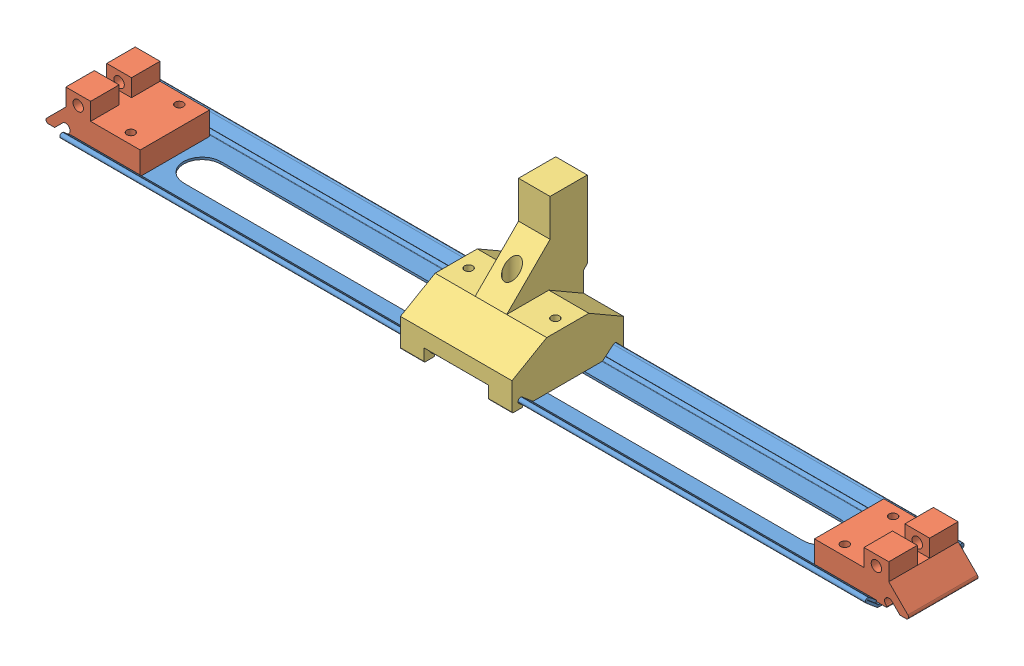
SolidWorks assembly bushing config, configuration Default. Lengths in mm.
Overall size (348 53.61 46.5).
4 component instances, 3 part files, 12 mates.
Components (placement in the parent):
- sheet metal gantry-1: sheet metal gantry [Default] at origin size (325 5.52 39.86)
- gantry holder-bushing-1: gantry holder-bushing [Default] at (-136 5.461 0) x (0 0 -1) z (-1 0 0) size (28 16.4 38)
- gantry holder-bushing-2: gantry holder-bushing [Default] at (136 5.588 0) x (0 0 1) z (1 0 0) size (28 16.4 38)
- hotend mount-bushing-1: hotend mount-bushing [Default] at (0 11.1125 0) x (0 0 1) z (1 0 0) size (46.5 52 45)
Mates (geometry in assembly coordinates):
- Coincident1: coordinate: point of sheet metal gantry-1; point of assembly
- Coincident2: coincident aligned: plane of ? through (-2.3369 1.8788 0) normal (0 0 1); plane of assembly through (0 0 0) normal (0 0 1)
- Tangent1: tangent anti-aligned: cylinder of sheet metal gantry-1 through (-162.5 4.8168 -18.6685) axis (-1 0 0) radius 0.812; plane of ? through (10.1631 5.6288 -8.4455) normal (0 -1 0)
- Coincident3: coincident anti-aligned: plane of gantry holder-bushing-1 through (-136 5.461 0) normal (0 0 -1); plane of assembly through (0 0 0) normal (0 0 1)
- Distance1: distance = 10.16 mm anti-aligned: plane of gantry holder-bushing-1 through (-166 10.16 -14) normal (0 1 0); plane of sheet metal gantry-1 through (162.5 0 15) normal (0 -1 0)
- Concentric1: concentric aligned: cylinder of sheet metal gantry-1 through (-144 0.889 9.75) axis (0 1 0) radius 2.15; cylinder of gantry holder-bushing-1 through (-144 10.16 9.75) axis (0 1 0) radius 1.65
- Concentric2: concentric aligned: cylinder of sheet metal gantry-1 through (144 0.889 -9.75) axis (0 1 0) radius 2.15; cylinder of gantry holder-bushing-2 through (144 10.287 -9.75) axis (0 1 0) radius 1.65
- Concentric3: concentric aligned: cylinder of sheet metal gantry-1 through (144 0.889 9.75) axis (0 1 0) radius 2.15; cylinder of gantry holder-bushing-2 through (144 10.287 9.75) axis (0 1 0) radius 1.65
- Coincident5: coincident anti-aligned: plane of sheet metal gantry-1 through (162.5 0.889 15) normal (0 1 0); plane of gantry holder-bushing-2 through (166 0.889 14) normal (0 -1 0)
- Coincident6: coincident aligned: plane of hotend mount-bushing-1 through (0 11.1125 0) normal (1 0 0); plane of assembly through (0 0 0) normal (1 0 0)
- Coincident7: coincident aligned: plane of hotend mount-bushing-1 through (0 11.1125 0) normal (0 0 1); plane of assembly through (0 0 0) normal (0 0 1)
- Coincident8: coincident anti-aligned: plane of sheet metal gantry-1 through (0 3.9902 16.8337) normal (0 0.766044 -0.642788); plane of hotend mount-bushing-1 through (-25 5.9513 19.1708) normal (0 -0.766044 0.642788)
